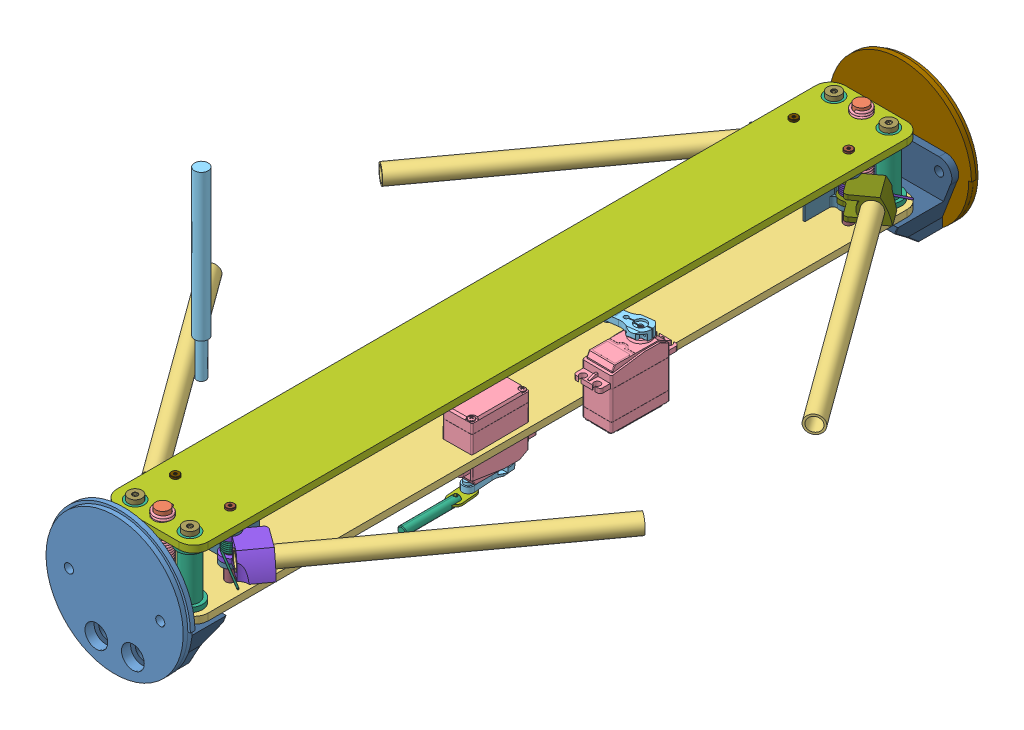
SolidWorks assembly Jettison_Spring_Mechanism, configuration Default. Lengths in mm.
Overall size (313.83 279.52 552.45).
64 component instances, 26 part files, 82 mates.
Components (placement in the parent):
- Bulkhead_4in_Inner_V2-1: Bulkhead_4in_Inner_V2 [Default] at (47.4239 60.2667 60.8416) size (99.01 97.19 6.35)
- Spring_Guide-1: Spring_Guide [Default] at (47.4239 43.7502 33.8541) x (-0.97506 0 0.221942) z (-0.221942 0 -0.97506) size (12.7 53.34 12.7)
- Drone_Base-1: Drone_Base [Default] at (79.1739 43.7502 -462.0809) x (0 0 1) z (-1 0 0) size (506.09 4.76 63.5)
- 0.5in_Spring-1: 0.5in_Spring [Default] at (47.4239 46.2902 33.8541) x (0.223835 0 -0.974627) z (0 -1 0) size (14.3 14.3 50.37)
- Extra_Guide_Pin-1: Extra_Guide_Pin [Default] at (51.8088 165.0986 11.2871) x (-0.805779 0 0.592216) z (-0.592216 0 -0.805779) size (9.53 127 9.53)
- Lathe_Double_Flange-3: Lathe_Double_Flange [Default] at (66.4739 48.5127 33.8541) x (0 1 0) z (0.057197 0 0.998363) size (47.62 17.46 17.46)
- Lathe_Double_Flange-4: Lathe_Double_Flange [Default] at (28.3739 48.5127 33.8541) x (0 1 0) z (0.048171 0 0.998839) size (47.62 17.46 17.46)
- Drone_Top222-1: Drone_Top222 [Default] at (15.6739 86.6127 44.0141) x (0 0 -1) z (1 0 0) size (506.09 4.76 69.85)
- Hinge_V333-1: Hinge_V333 [Default] at (47.3402 55.0083 -0.1791) x (-0.807999 0 -0.589183) z (0.589183 0 -0.807999) size (31.75 16.51 25.4)
- Bulkhead_4in_Inner_FWD_V2-1: Bulkhead_4in_Inner_FWD_V2 [Default] at (47.4239 60.2667 -478.9084) x (-1 0 0) z (0 0 -1) size (99.01 97.19 6.35)
- Guides_Support-1: Guides_Support [Default] at (47.4239 60.2667 60.8416) x (-1 0 0) z (0 0 -1) size (81.28 56.58 36.51)
- Guides_Support-2: Guides_Support [Default] at (47.4239 60.2667 -478.9084) size (81.28 56.58 36.51)
- 90666A003_Super-Corrosion-Resistant 316 Stainless Steel Socket Head Screw (1)-1: 90666A003_Super-Corrosion-Resistant 316 Stainless Steel Socket Head Screw (1) [90666A003] at (66.4739 44.544 33.8541) x (-0.839629 0 -0.543161) z (0 -1 0) size (5.74 5.74 14.66)
- 90666A003_Super-Corrosion-Resistant 316 Stainless Steel Socket Head Screw (1)-2: 90666A003_Super-Corrosion-Resistant 316 Stainless Steel Socket Head Screw (1) [90666A003] at (47.4239 44.544 33.8541) x (1 0 0) z (0 -1 0) size (5.74 5.74 14.66)
- 90666A003_Super-Corrosion-Resistant 316 Stainless Steel Socket Head Screw (1)-3: 90666A003_Super-Corrosion-Resistant 316 Stainless Steel Socket Head Screw (1) [90666A003] at (28.3739 44.544 33.8541) x (1 0 0) z (0 -1 0) size (5.74 5.74 14.66)
- 93330A621_Female Threaded Round Standoff-2: 93330A621_Female Threaded Round Standoff [93330A621] at (28.3739 81.8502 33.8541) x (0.944057 0 0.329782) z (0 -1 0) size (9.53 9.53 26.09)
- 93330A621_Female Threaded Round Standoff-3: 93330A621_Female Threaded Round Standoff [93330A621] at (66.4739 56.4502 33.8541) x (1 0 0) z (0 -1 0) size (9.53 9.53 26.09)
- 93330A621_Female Threaded Round Standoff-4: 93330A621_Female Threaded Round Standoff [93330A621] at (66.4739 81.8502 33.8541) x (1 0 0) z (0 -1 0) size (9.53 9.53 26.09)
- 93330A621_Female Threaded Round Standoff-5: 93330A621_Female Threaded Round Standoff [93330A621] at (28.3739 56.4502 33.8541) x (1 0 0) z (0 1 0) size (9.53 9.53 26.09)
- 91125A481_Female Threaded Round Standoff-1: 91125A481_Female Threaded Round Standoff [91125A481] at (28.3739 67.5627 5.9141) x (0.687063 0 -0.726598) z (0 -1 0) size (6.35 6.35 38.7)
- 91125A481_Female Threaded Round Standoff-2: 91125A481_Female Threaded Round Standoff [91125A481] at (66.4739 67.5627 5.9141) x (-0.999974 0 -0.007208) z (0 -1 0) size (6.35 6.35 38.7)
- Hinge_Outter-1: Hinge_Outter [Default] at (66.4739 58.9241 5.9141) x (0 0 -1) z (0 1 0) size (31.67 50.5 22.86)
- 9271K403_Torsion Spring (1)-1: 9271K403_Torsion Spring (1) [9271K403] at (66.4739 66.5441 5.9141) x (0 -1 0) z (0.866025 0 0.5) size (11.46 30.62 52.01)
- 90666A003_Super-Corrosion-Resistant 316 Stainless Steel Socket Head Screw (1)-5: 90666A003_Super-Corrosion-Resistant 316 Stainless Steel Socket Head Screw (1) [90666A003] at (66.4739 85.819 5.9141) x (1 0 0) z (0 1 0) size (5.74 5.74 14.66)
- MirrorHinge_V333-2: MirrorHinge_V333 [Default] at (47.5076 55.0083 -0.1791) x (0.807999 0 -0.589183) z (0.589183 0 0.807999) size (31.75 17.53 25.4)
- Mirror9271K403_Torsion Spring (1)-3: Mirror9271K403_Torsion Spring (1) [9271K403] at (28.3739 66.5441 5.9141) x (0 -1 0) z (0.866025 0 -0.5) size (11.46 30.62 52.01)
- Mirror90666A003_Super-Corrosion-Resistant 316 Stainless Steel Socket Head Screw (1)-8: Mirror90666A003_Super-Corrosion-Resistant 316 Stainless Steel Socket Head Screw (1) [90666A003] at (28.3739 85.819 5.9141) x (-1 0 0) z (0 -1 0) size (5.74 5.74 14.66)
- 90666A003_Super-Corrosion-Resistant 316 Stainless Steel Socket Head Screw (1)-9: 90666A003_Super-Corrosion-Resistant 316 Stainless Steel Socket Head Screw (1) [90666A003] at (66.4739 49.3065 5.9141) x (-0.837169 0 -0.546944) z (0 -1 0) size (5.74 5.74 14.66)
- Mirror90666A003_Super-Corrosion-Resistant 316 Stainless Steel Socket Head Screw (1)-9: Mirror90666A003_Super-Corrosion-Resistant 316 Stainless Steel Socket Head Screw (1) [90666A003] at (28.3739 49.3065 5.9141) x (0.999788 0 0.020576) z (0 1 0) size (5.74 5.74 14.66)
- MirrorHinge_V333-3: MirrorHinge_V333 [Default] at (47.3402 55.0083 -417.8878) x (-0.807999 0 0.589183) z (-0.589183 0 -0.807999) size (31.75 17.53 25.4)
- 91125A481_Female Threaded Round Standoff-4: 91125A481_Female Threaded Round Standoff [91125A481] at (66.4739 67.5587 -423.9809) x (-0.999974 0 0.007208) z (0 1 0) size (6.35 6.35 38.7)
- Mirror9271K403_Torsion Spring (1)-4: Mirror9271K403_Torsion Spring (1) [9271K403] at (66.4739 66.5441 -423.9809) x (0 -1 0) z (-0.866025 0 0.5) size (11.46 30.62 52.01)
- 90666A003_Super-Corrosion-Resistant 316 Stainless Steel Socket Head Screw (1)-10: 90666A003_Super-Corrosion-Resistant 316 Stainless Steel Socket Head Screw (1) [90666A003] at (66.4739 85.819 -423.9809) x (1 0 0) z (0 1 0) size (5.74 5.74 14.66)
- 90666A003_Super-Corrosion-Resistant 316 Stainless Steel Socket Head Screw (1)-11: 90666A003_Super-Corrosion-Resistant 316 Stainless Steel Socket Head Screw (1) [90666A003] at (66.4739 49.3065 -423.9809) x (-0.837169 0 0.546944) z (0 -1 0) size (5.74 5.74 14.66)
- Hinge_Outter-2: Hinge_Outter [Default] at (66.4739 81.7841 -423.9809) x (0 0 1) z (0 -1 0) size (31.67 50.5 22.86)
- MirrorMirrorHinge_V333-4: MirrorMirrorHinge_V333 [Default] at (47.5076 55.0083 -417.8878) x (0.807999 0 0.589183) z (-0.589183 0 0.807999) size (31.75 17.53 25.4)
- MirrorMirror9271K403_Torsion Spring (1)-5: MirrorMirror9271K403_Torsion Spring (1) [9271K403] at (28.3739 66.5441 -423.9809) x (0 -1 0) z (-0.866025 0 -0.5) size (11.46 30.62 52.01)
- Mirror90666A003_Super-Corrosion-Resistant 316 Stainless Steel Socket Head Screw (1)-10: Mirror90666A003_Super-Corrosion-Resistant 316 Stainless Steel Socket Head Screw (1) [90666A003] at (28.3739 49.3065 -423.9809) x (0.999788 0 -0.020576) z (0 1 0) size (5.74 5.74 14.66)
- 91125A481_Female Threaded Round Standoff-5: 91125A481_Female Threaded Round Standoff [91125A481] at (28.3739 67.5587 -423.9809) x (-0.687063 0 -0.726598) z (0 1 0) size (6.35 6.35 38.7)
- Mirror90666A003_Super-Corrosion-Resistant 316 Stainless Steel Socket Head Screw (1)-11: Mirror90666A003_Super-Corrosion-Resistant 316 Stainless Steel Socket Head Screw (1) [90666A003] at (28.3739 85.819 -423.9809) x (-1 0 0) z (0 -1 0) size (5.74 5.74 14.66)
- Lathe_Double_Flange-5: Lathe_Double_Flange [Default] at (66.4739 48.5127 -451.9209) x (0 1 0) z (-0.057197 0 0.998363) size (47.62 17.46 17.46)
- Lathe_Double_Flange-6: Lathe_Double_Flange [Default] at (28.3739 48.5127 -451.9209) x (0 1 0) z (-0.048171 0 0.998839) size (47.62 17.46 17.46)
- 5287T616_Ultra-Strength Lightweight Carbon Fiber Tube-1: 5287T616_Ultra-Strength Lightweight Carbon Fiber Tube [5287T616] at (138.2993 70.3541 -67.4544) x (0.796925 0.164995 0.581108) z (-0.589183 0 0.807999) size (12.32 12.32 203.2)
- 5287T616_Ultra-Strength Lightweight Carbon Fiber Tube-2: 5287T616_Ultra-Strength Lightweight Carbon Fiber Tube [5287T616] at (-43.4515 70.3541 -67.4544) x (0.807999 0 -0.589183) z (0.589183 0 0.807999) size (12.32 12.32 203.2)
- 5287T616_Ultra-Strength Lightweight Carbon Fiber Tube-3: 5287T616_Ultra-Strength Lightweight Carbon Fiber Tube [5287T616] at (138.2993 70.3541 -350.6125) x (0.807344 0.040256 -0.588706) z (0.589183 0 0.807999) size (12.32 12.32 203.2)
- 5287T616_Ultra-Strength Lightweight Carbon Fiber Tube-4: 5287T616_Ultra-Strength Lightweight Carbon Fiber Tube [5287T616] at (-43.4515 70.3541 -350.6125) x (0.34424 -0.904704 0.251016) z (0.589183 0 -0.807999) size (12.32 12.32 203.2)
- DS3225MG Servo 25Kg 4.8-6.8V-1: DS3225MG Servo 25Kg 4.8-6.8V [Default] at (89.5555 80.9571 -256.2953) x (-0.008727 0 0.999962) z (0 1 0) size (87.25 20.4 45.91)
- DS3225MG Servo 25Kg 4.8-6.8V-2: DS3225MG Servo 25Kg 4.8-6.8V [Default] at (65.4575 22.7751 -182.4591) x (0.008725 0.008511 0.999926) z (-0.000318 -0.999964 0.008514) size (87.25 20.4 45.91)
- SW2020 Aluminium 25T Servo Horn-1: SW2020 Aluminium 25T Servo Horn [Default] at (65.4569 20.7752 -182.442) x (0.08722 0.008453 0.996153) z (-0.000318 -0.999964 0.008514) size (35.39 14.8 6)
- SW2020 Aluminium 25T Servo Horn-2: SW2020 Aluminium 25T Servo Horn [Default] at (89.5555 82.9571 -256.2953) x (-0.990498 0 0.137525) z (0 1 0) size (35.39 14.8 6)
- pin_big-1: pin_big [Default] at (282.9549 59.6138 -35.2995) x (0.01461 0.008508 0.999857) z (-0.999893 0.000443 0.014607) size (40 6.07 6.12)
- pin_big-2: pin_big [Default] at (-88.4777 44.8033 -444.2436) x (-0.990498 0 0.137525) z (0.137525 0 0.990498) size (40 6.07 6.12)
- bolt_link_bolt-1: bolt_link_bolt [Default] at (-126.6561 44.855 -408.8811) x (-0.938408 0 0.345528) z (0.345528 0 0.938408) size (20 9.91 10)
- bolt_link_bolt-2: bolt_link_bolt [Default] at (291.2225 59.513 -52.5118) x (0.093176 0.008447 0.995614) z (-0.99565 0.00111 0.09317) size (20 9.91 10)
- 93330A621_Female Threaded Round Standoff-6: 93330A621_Female Threaded Round Standoff [93330A621] at (28.3739 56.4502 -451.9209) x (1 0 0) z (0 1 0) size (9.53 9.53 26.09)
- 93330A621_Female Threaded Round Standoff-7: 93330A621_Female Threaded Round Standoff [93330A621] at (28.3739 81.7527 -451.9209) x (-0.944057 0 0.329782) z (0 1 0) size (9.53 9.53 26.09)
- 93330A621_Female Threaded Round Standoff-8: 93330A621_Female Threaded Round Standoff [93330A621] at (66.4739 81.8502 -451.9209) x (1 0 0) z (0 -1 0) size (9.53 9.53 26.09)
- 93330A621_Female Threaded Round Standoff-9: 93330A621_Female Threaded Round Standoff [93330A621] at (66.4739 56.4502 -451.9209) x (1 0 0) z (0 -1 0) size (9.53 9.53 26.09)
- 0.5in_Spring-2: 0.5in_Spring [Default] at (47.4239 95.0582 -451.9209) x (0.223835 0 0.974627) z (0 1 0) size (14.3 14.3 50.37)
- Spring_Guide-2: Spring_Guide [Default] at (47.4239 43.7502 -451.9209) x (-0.97506 0 -0.221942) z (0.221942 0 -0.97506) size (12.7 53.34 12.7)
- 90666A003_Super-Corrosion-Resistant 316 Stainless Steel Socket Head Screw (1)-12: 90666A003_Super-Corrosion-Resistant 316 Stainless Steel Socket Head Screw (1) [90666A003] at (28.3739 44.544 -451.9209) x (1 0 0) z (0 -1 0) size (5.74 5.74 14.66)
- 90666A003_Super-Corrosion-Resistant 316 Stainless Steel Socket Head Screw (1)-13: 90666A003_Super-Corrosion-Resistant 316 Stainless Steel Socket Head Screw (1) [90666A003] at (47.4239 44.544 -451.9209) x (1 0 0) z (0 -1 0) size (5.74 5.74 14.66)
- 90666A003_Super-Corrosion-Resistant 316 Stainless Steel Socket Head Screw (1)-14: 90666A003_Super-Corrosion-Resistant 316 Stainless Steel Socket Head Screw (1) [90666A003] at (66.4739 44.544 -451.9209) x (-0.839629 0 0.543161) z (0 -1 0) size (5.74 5.74 14.66)
- Support_Bracket-1: Support_Bracket [Default] at (49.0114 17.0918 -474.1459) x (0 0 1) z (-1 0 0) size (539.75 46.58 3.17)
Mates (geometry in assembly coordinates):
- Concentric4: concentric aligned: cylinder of Spring_Guide-1 through (47.4239 97.0902 33.8541) axis (0 -1 0) radius 4.7498; cylinder of Drone_Base-1 through (47.4239 48.5127 33.8541) axis (0 -1 0) radius 8.89
- Concentric5: concentric aligned: cylinder of Spring_Guide-1 through (47.4239 97.0902 33.8541) axis (0 -1 0) radius 4.7498; circle of 0.5in_Spring-1
- Coincident11: coincident anti-aligned: plane of Spring_Guide-1 through (47.4239 46.2902 33.8541) normal (0 1 0); circle of 0.5in_Spring-1
- Coincident12: coincident anti-aligned: plane of Drone_Base-1 through (47.4239 48.5127 -451.9209) normal (0 1 0); plane of Lathe_Double_Flange-3 through (66.4739 48.5127 33.8541) normal (0 -1 0)
- Concentric15: concentric aligned: cylinder of Drone_Base-1 through (66.4739 48.5127 33.8541) axis (0 -1 0) radius 4.7625; cylinder of Lathe_Double_Flange-3 through (66.4739 67.5627 33.8541) axis (0 -1 0) radius 6.35
- Concentric16: concentric aligned: cylinder of Drone_Base-1 through (28.3739 48.5127 33.8541) axis (0 -1 0) radius 4.7625; cylinder of Lathe_Double_Flange-4 through (28.3739 67.5627 33.8541) axis (0 -1 0) radius 6.35
- Coincident13: coincident anti-aligned: plane of Drone_Base-1 through (47.4239 48.5127 -451.9209) normal (0 1 0); plane of Lathe_Double_Flange-4 through (28.3739 48.5127 33.8541) normal (0 -1 0)
- Coincident15: coincident aligned: plane of Drone_Base-1 through (69.0139 48.5127 44.0141) normal (0 0 1); plane of Drone_Top222-1 through (25.8339 91.3752 44.0141) normal (0 0 1)
- Concentric22: concentric anti-aligned: cylinder of Bulkhead_4in_Inner_V2-1 through (47.4239 60.2667 64.0166) axis (0 0 -1) radius 49.5046; cylinder of Bulkhead_4in_Inner_FWD_V2-1 through (47.4239 60.2667 -482.0834) axis (0 0 1) radius 49.5046
- Distance9: distance = 539.75 mm anti-aligned: plane of Bulkhead_4in_Inner_FWD_V2-1 through (47.4239 60.2667 -478.9084) normal (0 0 1); plane of Bulkhead_4in_Inner_V2-1 through (47.4239 60.2667 60.8416) normal (0 0 -1)
- Distance10: distance = 8.0036 mm anti-aligned: plane of Hinge_V333-1 through (92.7404 78.6091 1.4905) normal (0 1 0); plane of Drone_Top222-1 through (25.8339 86.6127 33.8541) normal (0 -1 0)
- Coincident35: coincident aligned: plane of Bulkhead_4in_Inner_V2-1 through (95.0489 60.2667 60.8416) normal (0 -1 0); plane of Bulkhead_4in_Inner_FWD_V2-1 through (97.5889 60.2667 -478.9084) normal (0 -1 0)
- Concentric26: concentric aligned: cylinder of Lathe_Double_Flange-3 through (66.4739 91.3752 33.8541) axis (0 -1 0) radius 6.35; cylinder of Drone_Top222-1 through (66.4739 91.3752 33.8541) axis (0 -1 0) radius 6.35
- Coincident37: coincident anti-aligned: plane of Lathe_Double_Flange-3 through (66.4739 86.6127 33.8541) normal (0 1 0); plane of Drone_Top222-1 through (25.8339 86.6127 33.8541) normal (0 -1 0)
- Coincident38: coincident anti-aligned: plane of Bulkhead_4in_Inner_V2-1 through (47.4239 60.2667 60.8416) normal (0 0 -1); plane of Guides_Support-1 through (34.7239 29.0314 60.8416) normal (0 0 1)
- Concentric27: concentric aligned: cylinder of Bulkhead_4in_Inner_V2-1 through (79.1739 60.2667 60.8416) axis (0 0 1) radius 3.175; cylinder of Guides_Support-1 through (79.1739 60.2667 59.2541) axis (0 0 1) radius 3.175
- Concentric28: concentric aligned: cylinder of Bulkhead_4in_Inner_V2-1 through (15.6739 60.2667 60.8416) axis (0 0 1) radius 3.175; cylinder of Guides_Support-1 through (15.6739 60.2667 59.2541) axis (0 0 1) radius 3.175
- Coincident41: coincident anti-aligned: plane of Guides_Support-1 through (47.4239 38.9877 24.3291) normal (0 -1 0); plane of 90666A003_Super-Corrosion-Resistant 316 Stainless Steel Socket Head Screw (1)-1 through (67.4259 38.9877 32.3825) normal (0 1 0)
- Concentric36: concentric anti-aligned: cylinder of Spring_Guide-1 through (47.4239 46.2902 33.8541) axis (0 -1 0) radius 6.35; cylinder of Guides_Support-1 through (47.4239 12.5782 33.8541) axis (0 1 0) radius 1.7526
- Coincident43: coincident anti-aligned: plane of Spring_Guide-1 through (47.4239 43.7502 33.8541) normal (0 -1 0); plane of Guides_Support-1 through (47.4239 43.7502 24.3291) normal (0 1 0)
- Coincident44: coincident anti-aligned: plane of Guides_Support-1 through (47.4239 38.9877 24.3291) normal (0 -1 0); plane of 90666A003_Super-Corrosion-Resistant 316 Stainless Steel Socket Head Screw (1)-2 through (47.4239 38.9877 35.6067) normal (0 1 0)
- Concentric39: concentric anti-aligned: cylinder of Guides_Support-1 through (47.4239 12.5782 33.8541) axis (0 1 0) radius 1.7526; circle of 90666A003_Super-Corrosion-Resistant 316 Stainless Steel Socket Head Screw (1)-2
- Coincident45: coincident anti-aligned: plane of Guides_Support-1 through (47.4239 38.9877 24.3291) normal (0 -1 0); plane of 90666A003_Super-Corrosion-Resistant 316 Stainless Steel Socket Head Screw (1)-3 through (28.3739 38.9877 35.6067) normal (0 1 0)
- Concentric40: concentric anti-aligned: cylinder of Guides_Support-1 through (28.3739 12.5782 33.8541) axis (0 1 0) radius 1.7526; circle of 90666A003_Super-Corrosion-Resistant 316 Stainless Steel Socket Head Screw (1)-3
- Concentric41: concentric anti-aligned: circle of 90666A003_Super-Corrosion-Resistant 316 Stainless Steel Socket Head Screw (1)-1; cylinder of 93330A621_Female Threaded Round Standoff-3 through (66.4739 43.7502 33.8541) axis (0 1 0) radius 4.7625
- Coincident46: coincident anti-aligned: plane of Guides_Support-1 through (47.4239 43.7502 24.3291) normal (0 1 0); plane of 93330A621_Female Threaded Round Standoff-3 through (66.4739 43.7502 33.8541) normal (0 -1 0)
- Coincident47: coincident anti-aligned: plane of 93330A621_Female Threaded Round Standoff-3 through (66.4739 69.1502 33.8541) normal (0 1 0); plane of 93330A621_Female Threaded Round Standoff-4 through (66.4739 69.1502 33.8541) normal (0 -1 0)
- Concentric42: concentric aligned: cylinder of 93330A621_Female Threaded Round Standoff-3 through (66.4739 43.7502 33.8541) axis (0 1 0) radius 4.7625; cylinder of 93330A621_Female Threaded Round Standoff-4 through (66.4739 69.1502 33.8541) axis (0 1 0) radius 4.7625
- Coincident48: coincident anti-aligned: plane of Guides_Support-1 through (47.4239 43.7502 24.3291) normal (0 1 0); plane of 93330A621_Female Threaded Round Standoff-5 through (28.3739 43.7502 33.8541) normal (0 -1 0)
- Concentric43: concentric aligned: circle of 90666A003_Super-Corrosion-Resistant 316 Stainless Steel Socket Head Screw (1)-3; cylinder of 93330A621_Female Threaded Round Standoff-5 through (28.3739 69.1502 33.8541) axis (0 -1 0) radius 4.7625
- Concentric44: concentric anti-aligned: cylinder of 93330A621_Female Threaded Round Standoff-2 through (28.3739 69.1502 33.8541) axis (0 1 0) radius 4.7625; cylinder of 93330A621_Female Threaded Round Standoff-5 through (28.3739 69.1502 33.8541) axis (0 -1 0) radius 4.7625
- Coincident50: coincident anti-aligned: plane of 93330A621_Female Threaded Round Standoff-2 through (28.3739 69.1502 33.8541) normal (0 -1 0); plane of 93330A621_Female Threaded Round Standoff-5 through (28.3739 69.1502 33.8541) normal (0 1 0)
- Concentric45: concentric anti-aligned: cylinder of Lathe_Double_Flange-3 through (66.4739 551.7502 33.8541) axis (0 -1 0) radius 4.7625; cylinder of 93330A621_Female Threaded Round Standoff-4 through (66.4739 69.1502 33.8541) axis (0 1 0) radius 4.7625
- Concentric46: concentric anti-aligned: cylinder of Lathe_Double_Flange-4 through (28.3739 551.7502 33.8541) axis (0 -1 0) radius 4.7625; cylinder of 93330A621_Female Threaded Round Standoff-2 through (28.3739 69.1502 33.8541) axis (0 1 0) radius 4.7625
- LimitDistance1: limit distance = 0 mm anti-aligned: plane of Drone_Base-1 through (47.4239 43.7502 -451.9209) normal (0 -1 0); plane of Guides_Support-1 through (47.4239 43.7502 24.3291) normal (0 1 0)
- Coincident52: coincident anti-aligned: plane of Drone_Top222-1 through (25.8339 86.6127 33.8541) normal (0 -1 0); plane of 91125A481_Female Threaded Round Standoff-2 through (66.4739 86.6127 5.9141) normal (0 1 0)
- Concentric50: concentric anti-aligned: cylinder of Drone_Top222-1 through (28.3739 91.3752 5.9141) axis (0 -1 0) radius 1.905; cylinder of 91125A481_Female Threaded Round Standoff-1 through (28.3739 48.5127 5.9141) axis (0 1 0) radius 3.175
- Coincident53: coincident anti-aligned: plane of Drone_Top222-1 through (25.8339 86.6127 33.8541) normal (0 -1 0); plane of 91125A481_Female Threaded Round Standoff-1 through (28.3739 86.6127 5.9141) normal (0 1 0)
- Concentric51: concentric anti-aligned: cylinder of 91125A481_Female Threaded Round Standoff-2 through (66.4739 48.5127 5.9141) axis (0 1 0) radius 3.175; cylinder of Hinge_Outter-1 through (66.4739 81.7841 5.9141) axis (0 -1 0) radius 3.175
- Parallel7: parallel anti-aligned: plane of Bulkhead_4in_Inner_V2-1 through (47.4239 60.2667 60.8416) normal (0 0 -1); plane of Hinge_Outter-1 through (60.2001 43.2186 5.9141) normal (0 0 1)
- Concentric53: concentric anti-aligned: cylinder of Drone_Top222-1 through (66.4739 91.3752 5.9141) axis (0 -1 0) radius 1.905; cylinder of 91125A481_Female Threaded Round Standoff-2 through (66.4739 48.5127 5.9141) axis (0 1 0) radius 3.175
- Concentric54: concentric aligned: cylinder of Hinge_V333-1 through (66.4739 53.2091 5.9141) axis (0 1 0) radius 3.175; cylinder of 91125A481_Female Threaded Round Standoff-2 through (66.4739 48.5127 5.9141) axis (0 1 0) radius 3.175
- Coincident55: coincident anti-aligned: plane of Bulkhead_4in_Inner_FWD_V2-1 through (47.4239 60.2667 -478.9084) normal (0 0 1); plane of Guides_Support-2 through (60.1239 29.0314 -478.9084) normal (0 0 -1)
- Concentric55: concentric aligned: cylinder of Bulkhead_4in_Inner_FWD_V2-1 through (15.6739 60.2667 -478.9084) axis (0 0 -1) radius 3.175; cylinder of Guides_Support-2 through (15.6739 60.2667 -477.3209) axis (0 0 -1) radius 3.175
- Concentric56: concentric aligned: cylinder of Bulkhead_4in_Inner_FWD_V2-1 through (79.1739 60.2667 -478.9084) axis (0 0 -1) radius 3.175; cylinder of Guides_Support-2 through (79.1739 60.2667 -477.3209) axis (0 0 -1) radius 3.175
- Coincident56: coincident anti-aligned: plane of Hinge_V333-1 through (92.7404 78.6091 1.4905) normal (0 1 0); plane of Hinge_Outter-1 through (66.4739 78.6091 5.9141) normal (0 -1 0)
- Coincident57: coincident anti-aligned: cylinder of 91125A481_Female Threaded Round Standoff-2 through (66.4739 48.5127 5.9141) axis (0 1 0) radius 3.175; circle of 9271K403_Torsion Spring (1)-1
- Distance12: distance = 1.27 mm: line of 9271K403_Torsion Spring (1)-1 through (66.4739 66.5441 5.9141) axis (-1 0 0); plane of Hinge_V333-1 through (84.4048 65.2741 -4.5877) normal (0 1 0)
- Parallel8: parallel: plane of Hinge_Outter-1 through (61.4701 58.9241 5.9141) normal (1 0 0); line of 9271K403_Torsion Spring (1)-1 through (61.3939 66.5441 5.9141) axis (0 0 -1)
- Concentric57: concentric anti-aligned: cylinder of Drone_Top222-1 through (66.4739 91.3752 5.9141) axis (0 -1 0) radius 1.905; circle of 90666A003_Super-Corrosion-Resistant 316 Stainless Steel Socket Head Screw (1)-5
- Coincident60: coincident anti-aligned: plane of Drone_Top222-1 through (25.8339 91.3752 33.8541) normal (0 1 0); plane of 90666A003_Super-Corrosion-Resistant 316 Stainless Steel Socket Head Screw (1)-5 through (66.4739 91.3752 4.1615) normal (0 -1 0)
- Concentric58: concentric aligned: cylinder of Drone_Base-1 through (66.4739 48.5127 5.9141) axis (0 -1 0) radius 1.905; circle of 90666A003_Super-Corrosion-Resistant 316 Stainless Steel Socket Head Screw (1)-9
- Coincident61: coincident anti-aligned: plane of Drone_Base-1 through (47.4239 43.7502 -451.9209) normal (0 -1 0); plane of 90666A003_Super-Corrosion-Resistant 316 Stainless Steel Socket Head Screw (1)-9 through (67.4325 43.7502 4.4468) normal (0 1 0)
- Concentric59: concentric anti-aligned: cylinder of Drone_Base-1 through (28.3739 48.5127 5.9141) axis (0 -1 0) radius 1.905; circle of Mirror90666A003_Super-Corrosion-Resistant 316 Stainless Steel Socket Head Screw (1)-9
- Coincident62: coincident anti-aligned: plane of Drone_Base-1 through (47.4239 43.7502 -451.9209) normal (0 -1 0); plane of Mirror90666A003_Super-Corrosion-Resistant 316 Stainless Steel Socket Head Screw (1)-9 through (28.41 43.7502 4.1618) normal (0 1 0)
- Concentric60: concentric anti-aligned: cylinder of Hinge_V333-1 through (89.6623 70.3541 -0.754) axis (-0.589183 0 0.807999) radius 6.1595; cylinder of 5287T616_Ultra-Strength Lightweight Carbon Fiber Tube-1 through (78.4383 70.3541 14.6384) axis (0.589183 0 -0.807999) radius 6.1595
- Coincident63: coincident aligned: plane of Hinge_V333-1 through (83.9186 62.0991 18.6345) normal (-0.589183 0 0.807999); plane of 5287T616_Ultra-Strength Lightweight Carbon Fiber Tube-1 through (78.4383 70.3541 14.6384) normal (-0.589183 0 0.807999)
- Concentric61: concentric anti-aligned: cylinder of MirrorHinge_V333-2 through (5.1856 70.3541 -0.754) axis (0.589183 0 0.807999) radius 6.1595; cylinder of 5287T616_Ultra-Strength Lightweight Carbon Fiber Tube-2 through (16.4095 70.3541 14.6384) axis (-0.589183 0 -0.807999) radius 6.1595
- Coincident64: coincident aligned: plane of MirrorHinge_V333-2 through (10.9292 62.0991 18.6345) normal (0.589183 0 0.807999); plane of 5287T616_Ultra-Strength Lightweight Carbon Fiber Tube-2 through (16.4095 70.3541 14.6384) normal (0.589183 0 0.807999)
- Coincident65: coincident aligned: plane of MirrorMirrorHinge_V333-4 through (10.9292 62.0991 -436.7014) normal (0.589183 0 -0.807999); plane of 5287T616_Ultra-Strength Lightweight Carbon Fiber Tube-4 through (16.4095 70.3541 -432.7052) normal (0.589183 0 -0.807999)
- Concentric62: concentric anti-aligned: cylinder of MirrorMirrorHinge_V333-4 through (5.1856 70.3541 -417.3128) axis (0.589183 0 -0.807999) radius 6.1595; cylinder of 5287T616_Ultra-Strength Lightweight Carbon Fiber Tube-4 through (16.4095 70.3541 -432.7052) axis (-0.589183 0 0.807999) radius 6.1595
- Concentric63: concentric aligned: cylinder of MirrorHinge_V333-3 through (89.6623 70.3541 -417.3128) axis (-0.589183 0 -0.807999) radius 6.1595; cylinder of 5287T616_Ultra-Strength Lightweight Carbon Fiber Tube-3 through (198.1603 70.3541 -268.5197) axis (-0.589183 0 -0.807999) radius 6.1595
- Coincident66: coincident aligned: plane of MirrorHinge_V333-3 through (83.9186 62.0991 -436.7014) normal (-0.589183 0 -0.807999); plane of 5287T616_Ultra-Strength Lightweight Carbon Fiber Tube-3 through (78.4383 70.3541 -432.7052) normal (-0.589183 0 -0.807999)
- Lock2: lock: unknown of MirrorMirrorHinge_V333-4; unknown of 5287T616_Ultra-Strength Lightweight Carbon Fiber Tube-4
- Lock3: lock: unknown of MirrorHinge_V333-3; unknown of 5287T616_Ultra-Strength Lightweight Carbon Fiber Tube-3
- Lock4: lock: unknown of Hinge_V333-1; unknown of 5287T616_Ultra-Strength Lightweight Carbon Fiber Tube-1
- Lock5: lock: unknown of MirrorHinge_V333-2; unknown of 5287T616_Ultra-Strength Lightweight Carbon Fiber Tube-2
- Concentric68: concentric aligned: cone of DS3225MG Servo 25Kg 4.8-6.8V-2; cone of SW2020 Aluminium 25T Servo Horn-1 through (65.4588 26.775 -182.4931) axis (-0.000318 -0.999964 0.008514)
- Coincident72: coincident anti-aligned: plane of DS3225MG Servo 25Kg 4.8-6.8V-2 through (65.4588 26.775 -182.4931) normal (-0.000318 -0.999964 0.008514); plane of SW2020 Aluminium 25T Servo Horn-1 through (65.4588 26.775 -182.4931) normal (0.000318 0.999964 -0.008514)
- Concentric69: concentric aligned: circle of DS3225MG Servo 25Kg 4.8-6.8V-1; cylinder of SW2020 Aluminium 25T Servo Horn-2 through (89.5555 81.4571 -256.2953) axis (0 1 0) radius 4
- Coincident74: coincident anti-aligned: plane of DS3225MG Servo 25Kg 4.8-6.8V-1 through (89.5555 76.9571 -256.2953) normal (0 1 0); plane of SW2020 Aluminium 25T Servo Horn-2 through (89.5555 76.9571 -256.2953) normal (0 -1 0)
- Coincident75: coincident anti-aligned: plane of pin_big-2 through (89.8755 84.4571 -259.0059) normal (0 -1 0); plane of bolt_link_bolt-1 through (47.2019 84.4571 -252.8131) normal (0 1 0)
- Concentric70: concentric aligned: circle of pin_big-2; circle of bolt_link_bolt-1
- Concentric71: concentric aligned: circle of pin_big-1; circle of bolt_link_bolt-2
- Coincident76: coincident anti-aligned: plane of pin_big-1 through (73.3349 20.7076 -143.1051) normal (-0.000318 -0.999964 0.008514); plane of bolt_link_bolt-2 through (75.4034 20.719 -141.69) normal (0.000318 0.999964 -0.008514)
- Concentric72: concentric anti-aligned: circle of SW2020 Aluminium 25T Servo Horn-1; circle of bolt_link_bolt-2
- Coincident78: coincident anti-aligned: plane of SW2020 Aluminium 25T Servo Horn-1 through (67.5515 25.0779 -158.5693) normal (0.000318 0.999964 -0.008514); plane of bolt_link_bolt-2 through (66.4804 25.1081 -155.0633) normal (-0.000318 -0.999964 0.008514)
- Coincident79: coincident anti-aligned: plane of SW2020 Aluminium 25T Servo Horn-2 through (89.5555 82.9571 -256.2953) normal (0 1 0); plane of bolt_link_bolt-1 through (47.2019 82.9571 -252.8131) normal (0 -1 0)
- Concentric73: concentric anti-aligned: cylinder of SW2020 Aluminium 25T Servo Horn-2 through (65.7836 75.9571 -252.9947) axis (0 1 0) radius 1.25; circle of bolt_link_bolt-1
- Coincident80: coincident anti-aligned: plane of Guides_Support-1 through (49.0114 20.2668 60.8416) normal (-1 0 0); plane of Support_Bracket-1 through (49.0114 17.0918 -474.1459) normal (1 0 0)
- Coincident81: coincident anti-aligned: plane of Guides_Support-1 through (47.4239 60.2667 56.0791) normal (0 0 -1); plane of Support_Bracket-1 through (45.8364 17.0918 56.0791) normal (0 0 1)
- Coincident82: coincident anti-aligned: plane of Guides_Support-1 through (49.0114 20.2668 60.8416) normal (0 1 0); plane of Support_Bracket-1 through (45.8364 20.2668 56.0791) normal (0 -1 0)
